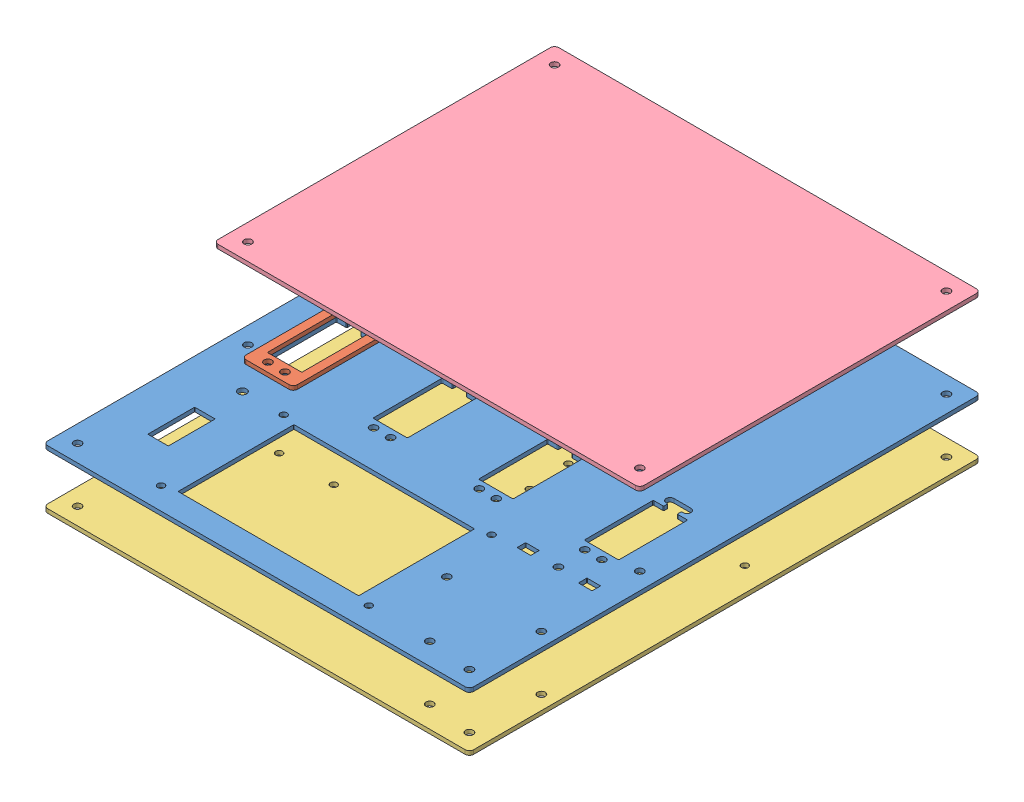
SolidWorks assembly 2D_Servo_Assm, configuration Default. Lengths in mm.
Overall size (250 86.76 300).
4 component instances, 4 part files, 9 mates.
Components (placement in the parent):
- 2D_Servo_Base-1: 2D_Servo_Base [Default] at origin size (250 2.38 300)
- Part3^2D_Servo_Assm-1: Part3^2D_Servo_Assm [Default] at (-14.493 2.3813 94.1299) size (30.2 2.38 60.5) (virtual)
- Part4^2D_Servo_Assm-1: Part4^2D_Servo_Assm [Default] at (0 -32 0) size (250 2.38 300) (virtual)
- Part5^2D_Servo_Assm-1: Part5^2D_Servo_Assm [Default] at (0 52.3812 0) size (250 2.38 200) (virtual)
Mates (geometry in assembly coordinates):
- Coincident1: coincident anti-aligned: plane of 2D_Servo_Base-1 through (0 2.3813 0) normal (0 1 0); plane of Part3^2D_Servo_Assm-1 through (-14.493 2.3813 94.1299) normal (0 -1 0)
- Distance1: distance = 16.9 mm aligned: plane of Part3^2D_Servo_Assm-1 through (16.9 4.7625 -160) normal (-1 0 0); plane of 2D_Servo_Base-1 through (0 2.3813 0) normal (-1 0 0)
- Distance2: distance = 99.5 mm aligned: plane of Part3^2D_Servo_Assm-1 through (16.9 4.7625 -99.5) normal (0 0 1); plane of 2D_Servo_Base-1 through (0 2.3813 0) normal (0 0 1)
- Distance3: distance = 32 mm aligned: plane of Part4^2D_Servo_Assm-1 through (2.5 -29.6187 -2.5) normal (0 1 0); plane of 2D_Servo_Base-1 through (0 2.3813 0) normal (0 1 0)
- Concentric1: concentric anti-aligned: cylinder of 2D_Servo_Base-1 through (10 0 -10) axis (0 1 0) radius 2.25; cylinder of Part4^2D_Servo_Assm-1 through (10 -29.6187 -10) axis (0 -1 0) radius 2.25
- Concentric2: concentric anti-aligned: cylinder of 2D_Servo_Base-1 through (240 0 -10) axis (0 1 0) radius 2.25; cylinder of Part4^2D_Servo_Assm-1 through (240 -29.6187 -10) axis (0 -1 0) radius 2.25
- Distance4: distance = 50 mm anti-aligned: plane of 2D_Servo_Base-1 through (0 2.3813 0) normal (0 1 0); plane of Part5^2D_Servo_Assm-1 through (247.5 52.3812 -297.5) normal (0 -1 0)
- Concentric3: concentric anti-aligned: cylinder of 2D_Servo_Base-1 through (10 0 -110) axis (0 1 0) radius 2.25; cylinder of Part5^2D_Servo_Assm-1 through (10 54.7625 -110) axis (0 -1 0) radius 2.25
- Concentric4: concentric anti-aligned: cylinder of 2D_Servo_Base-1 through (240 0 -110) axis (0 1 0) radius 2.25; cylinder of Part5^2D_Servo_Assm-1 through (240 54.7625 -110) axis (0 -1 0) radius 2.25
